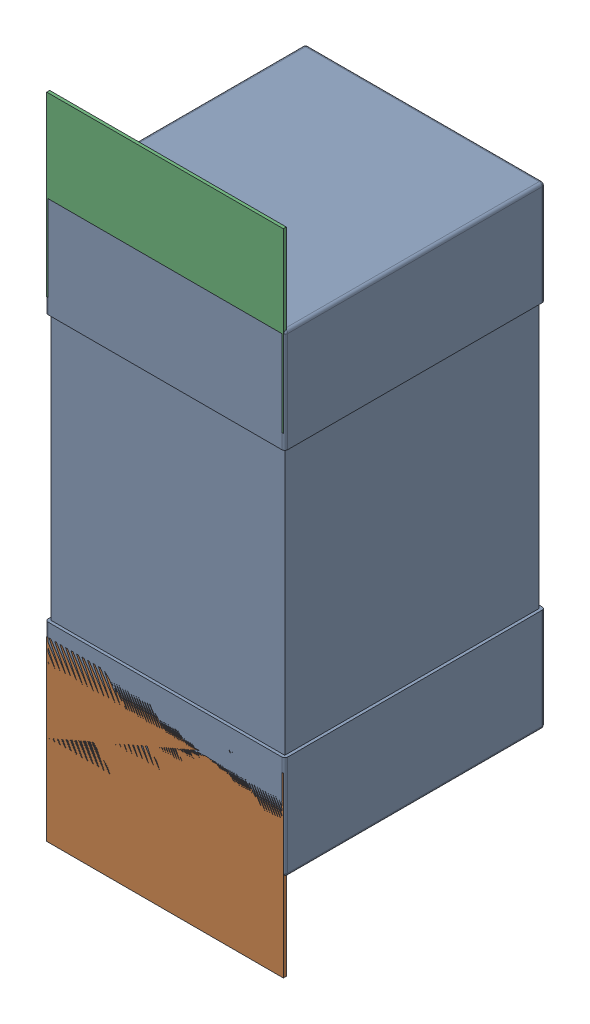
SolidWorks assembly C111, configuration Défaut. Lengths in mm.
Overall size (0.81 2.19 0.88).
5 component instances, 2 part files, 0 mates.
Components (placement in the parent):
- 0603_C-1: 0603_C [Défaut] at (3.9878 -9.4544 -2.0818) x (0 1 0) z (0 0 -1) size (1.6 0.81 0.88)
- 8260087904-1: 8260087904 [Défaut] at (3.9878 -9.7993 -2.0918) size (0.8 0.6 0.01)
  - Extruded_1211-1: Extruded_1211 [Défaut] at origin size (0.8 0.6 0.01)
- 8260087904-2: 8260087904 [Défaut] at (3.9878 -8.2044 -2.0918) size (0.8 0.6 0.01)
  - Extruded_1211-1: Extruded_1211 [Défaut] at origin size (0.8 0.6 0.01)
